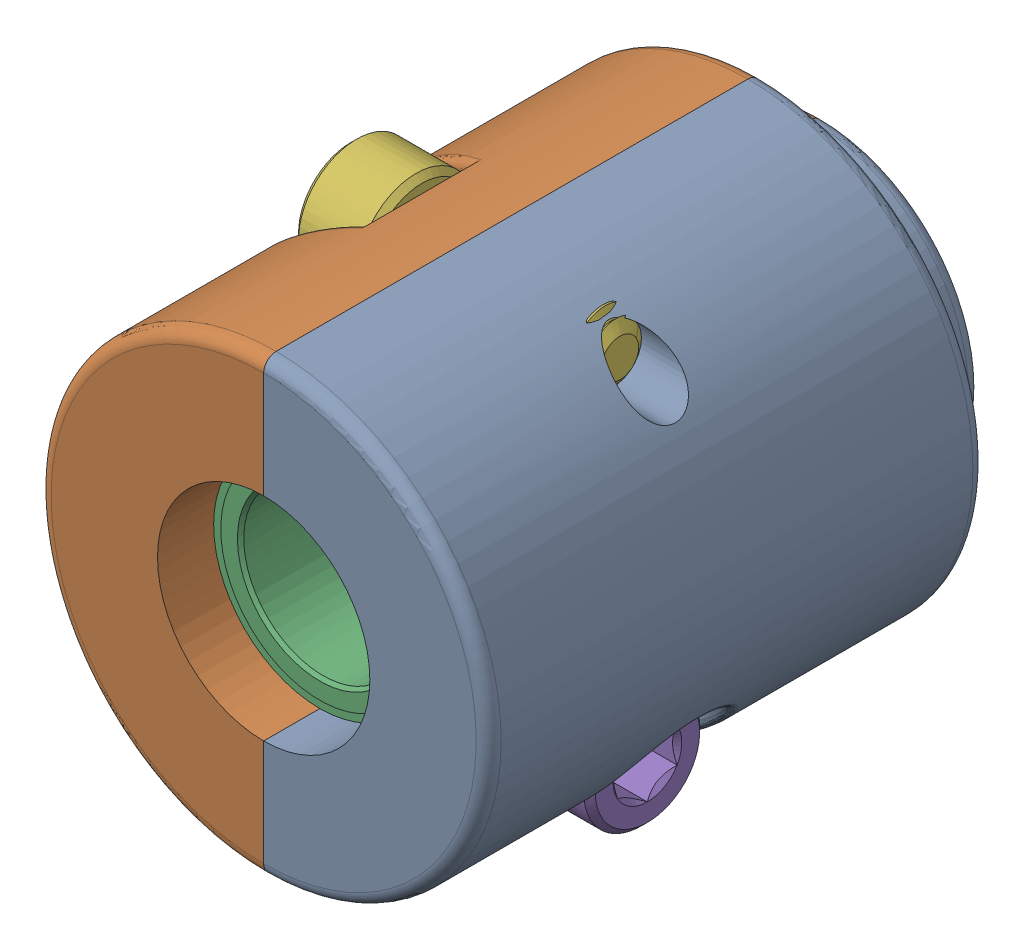
SolidWorks assembly 217-4098-100 Rev1, configuration Default. Lengths in mm.
Overall size (18.03 19.79 22.46).
6 component instances, 4 part files, 0 mates.
Components (placement in the parent):
- 217-4098-006 Rev2-1: 217-4098-006 Rev2 [Default] at (0 0 -4.6312) x (0 -1 0) z (0 0 -1) size (18.09 11.02 22.46)
- 217-4098-006 Rev2-2: 217-4098-006 Rev2 [Default] at (0 0 -4.6312) x (0 1 0) z (0 0 -1) size (18.09 11.02 22.46)
- 217-3489-001 Rev1-1: 217-3489-001 Rev1 [Default] at (0 0 -4.6312) x (0 0 1) z (-0.980217 -0.197926 0) size (4.77 12.7 12.7)
- 97633A130_97633A130_grv-1: 97633A130_97633A130_grv [Default] at (0 0 -7.33) x (0 0 -1) z (0.979861 0.199683 0) size (0.64 8.74 7.34)
- 91251A107_91251A107-1: 91251A107_91251A107 [Default] at (-4.8375 -6.735 -9.4343) x (0 0.863883 -0.503692) z (-1 0 0) size (4.65 4.65 10.79)
- 91251A107_91251A107-2: 91251A107_91251A107 [Default] at (4.8375 6.735 -9.4343) x (0 0.470889 -0.882193) z (1 0 0) size (4.65 4.65 10.79)
